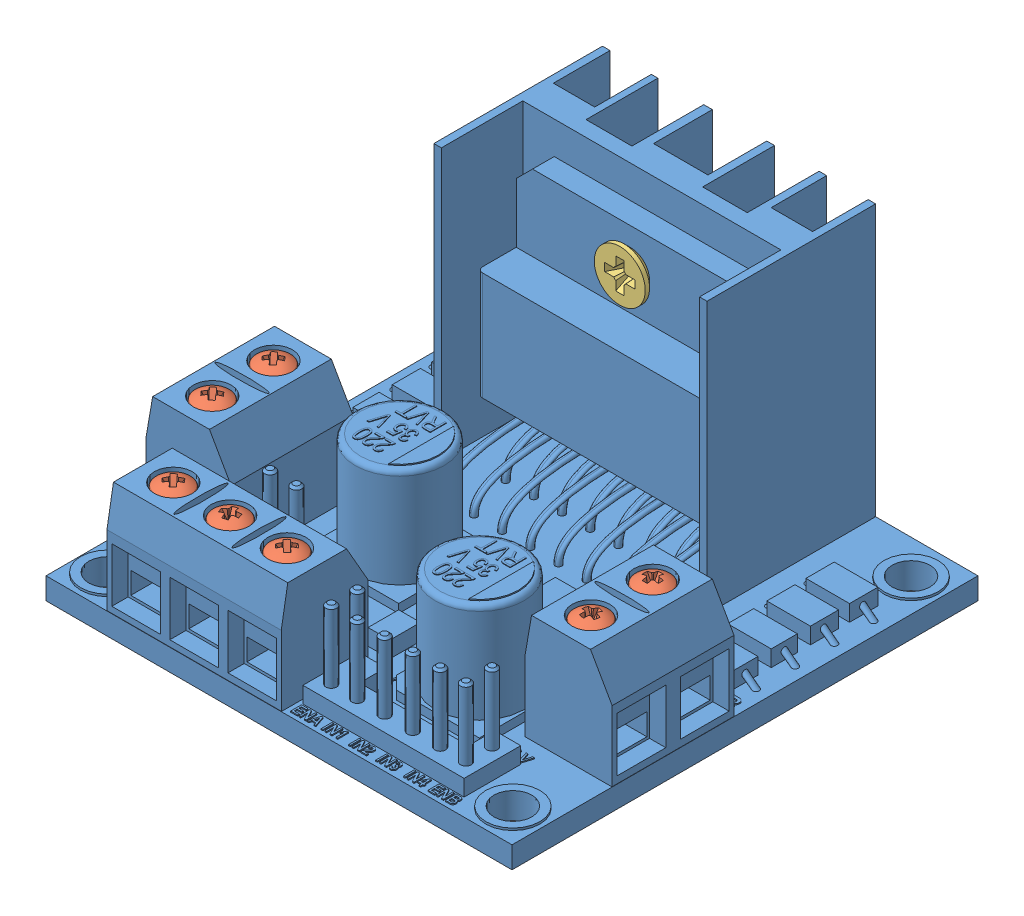
SolidWorks assembly L298N Stepper Motor Driver Assembly1, configuration Default. Lengths in mm.
Overall size (43 28.01 43).
9 component instances, 3 part files, 0 mates.
Components (placement in the parent):
- L298N Stepper Motor Driver (Red)-Part File_1-1: L298N Stepper Motor Driver (Red)-Part File_1 [Default] at (16.8606 10.1012 32.1341) size (43 28.01 43)
- pan head cross recess screw_iso_ISO 7045 - M1.6 x 4 - Z - 4N_1-1: pan head cross recess screw_iso_ISO 7045 - M1.6 x 4 - Z - 4N_1 [Default] at (-1.3394 22.4012 35.9476) x (0 -1 0) z (-0.742963 0 0.669332) size (5.74 3.2 3.38)
- pan head cross recess screw_iso_ISO 7045 - M1.6 x 4 - Z - 4N_1-2: pan head cross recess screw_iso_ISO 7045 - M1.6 x 4 - Z - 4N_1 [Default] at (-1.3394 22.4012 41.5921) x (0 -1 0) z (-0.751552 0 0.659674) size (5.74 3.2 3.38)
- pan head cross recess screw_iso_ISO 7045 - M1.6 x 4 - Z - 4N_1-3: pan head cross recess screw_iso_ISO 7045 - M1.6 x 4 - Z - 4N_1 [Default] at (3.7852 22.4012 50.3107) x (0 -1 0) z (0.734198 0 -0.678936) size (5.74 3.2 3.38)
- pan head cross recess screw_iso_ISO 7045 - M1.6 x 4 - Z - 4N_1-4: pan head cross recess screw_iso_ISO 7045 - M1.6 x 4 - Z - 4N_1 [Default] at (14.2688 22.4012 50.3107) x (0 -1 0) z (0.720108 0 0.693862) size (5.74 3.2 3.38)
- pan head cross recess screw_iso_ISO 7045 - M1.6 x 4 - Z - 4N_1-5: pan head cross recess screw_iso_ISO 7045 - M1.6 x 4 - Z - 4N_1 [Default] at (9.027 22.4012 50.3107) x (0 -1 0) z (0.308372 0 0.951266) size (5.74 3.2 3.38)
- pan head cross recess screw_iso_ISO 7045 - M1.6 x 4 - Z - 4N_1-6: pan head cross recess screw_iso_ISO 7045 - M1.6 x 4 - Z - 4N_1 [Default] at (33.6606 22.4012 35.9476) x (0 -1 0) z (0 0 1) size (5.74 3.2 3.38)
- pan head cross recess screw_iso_ISO 7045 - M1.6 x 4 - Z - 4N_1-7: pan head cross recess screw_iso_ISO 7045 - M1.6 x 4 - Z - 4N_1 [Default] at (33.6606 22.4012 41.6421) x (0 -1 0) z (-0.222944 0 0.974831) size (5.74 3.2 3.38)
- countersunk flat head cross recess screw_iso_ISO 7046-1 - M2.5 x 3 - Z - 3N_1-1: countersunk flat head cross recess screw_iso_ISO 7046-1 - M2.5 x 3 - Z - 3N_1 [Default] at (16.3567 30.6012 21.6857) x (0 0 -1) z (1 0 0) size (3 4.7 4.7)
